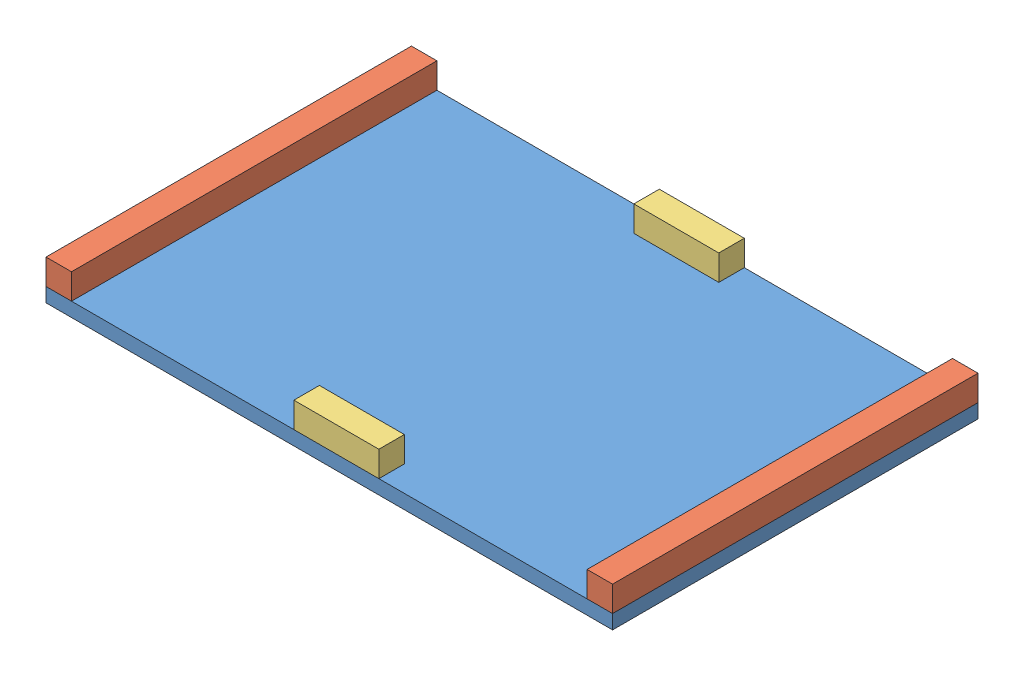
SolidWorks assembly Assemblage2, configuration Default. Lengths in mm.
Overall size (400 28 258).
5 component instances, 3 part files, 12 mates.
Components (placement in the parent):
- support_carte-1: support_carte [Default] at (-214.8622 5.6641 129.5976) size (400 10 258)
- linteau_18x18_L258_bleu-1: linteau_18x18_L258_bleu [Default] at (-214.8622 15.6641 129.5976) size (18 18 258)
- linteau_18x18_L258_bleu-2: linteau_18x18_L258_bleu [Default] at (167.1378 15.6641 129.5976) size (18 18 258)
- linteau_18x18_L60_bleu-1: linteau_18x18_L60_bleu [Default] at (20.1378 15.6641 -110.4024) x (0 0 -1) z (1 0 0) size (18 18 60)
- linteau_18x18_L60_bleu-2: linteau_18x18_L60_bleu [Default] at (-39.8622 15.6641 111.5976) x (0 0 1) z (-1 0 0) size (18 18 60)
Mates (geometry in assembly coordinates):
- Coïncidente1: coincident: plane of support_carte-1 through (-214.8622 15.6641 -128.4024) normal (0 1 0); plane of linteau_18x18_L258_bleu-1 through (-214.8622 15.6641 -128.4024) normal (0 -1 0)
- Coïncidente2: coincident: plane of support_carte-1 through (-214.8622 15.6641 129.5976) normal (0 0 1); plane of linteau_18x18_L258_bleu-1 through (-214.8622 33.6641 129.5976) normal (0 0 1)
- Coïncidente3: coincident: plane of support_carte-1 through (-214.8622 15.6641 129.5976) normal (-1 0 0); plane of linteau_18x18_L258_bleu-1 through (-214.8622 15.6641 -128.4024) normal (-1 0 0)
- Coïncidente4: coincident: plane of support_carte-1 through (-214.8622 15.6641 -128.4024) normal (0 1 0); plane of linteau_18x18_L258_bleu-2 through (167.1378 15.6641 -128.4024) normal (0 -1 0)
- Coïncidente5: coincident: plane of support_carte-1 through (185.1378 15.6641 129.5976) normal (1 0 0); plane of linteau_18x18_L258_bleu-2 through (185.1378 15.6641 -128.4024) normal (1 0 0)
- Coïncidente6: coincident: plane of support_carte-1 through (-214.8622 15.6641 129.5976) normal (0 0 1); plane of linteau_18x18_L258_bleu-2 through (167.1378 33.6641 129.5976) normal (0 0 1)
- Coïncidente7: coincident anti-aligned: plane of support_carte-1 through (-214.8622 15.6641 -128.4024) normal (0 1 0); plane of ? through (-49.8819 15.6641 -110.4024) normal (0 -1 0)
- Coïncidente8: coincident anti-aligned: plane of support_carte-1 through (-214.8622 15.6641 -128.4024) normal (0 1 0); plane of ? through (10.1181 15.6641 111.5976) normal (0 -1 0)
- Coïncidente9: coincident aligned: plane of ? through (10.1181 15.6641 129.5976) normal (0 0 1); plane of support_carte-1 through (-214.8622 15.6641 129.5976) normal (0 0 1)
- Coïncidente10: coincident aligned: plane of ? through (-49.8819 15.6641 -128.4024) normal (0 0 -1); plane of support_carte-1 through (-214.8622 15.6641 -128.4024) normal (0 0 -1)
- Coïncidente11: coincident aligned: plane of ? through (-49.8819 33.6641 -110.4024) normal (-1 0 0); plane of ? through (-49.8819 33.6641 111.5976) normal (-1 0 0)
- Distance1: distance = 175 mm aligned: plane of linteau_18x18_L60_bleu-1 through (-39.8622 33.6641 -110.4024) normal (-1 0 0); plane of support_carte-1 through (-214.8622 15.6641 129.5976) normal (-1 0 0)
